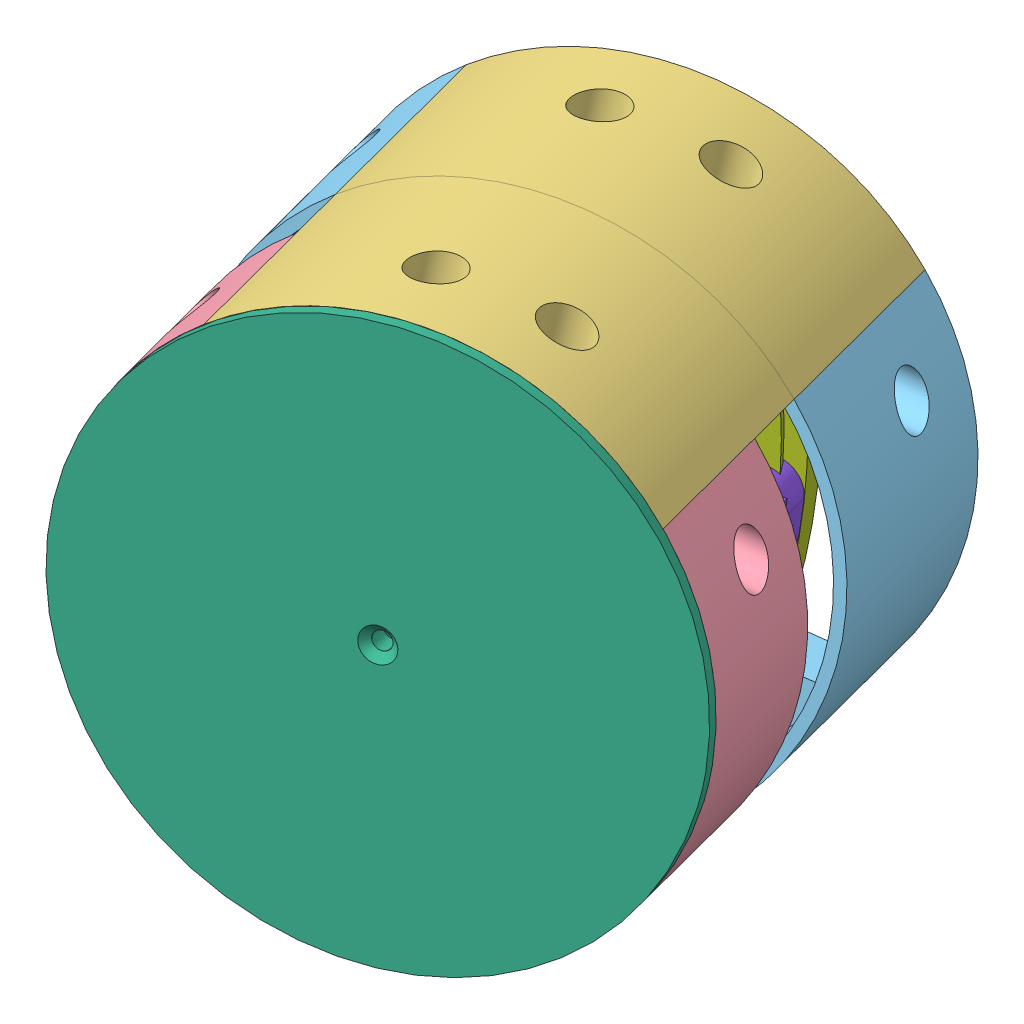
SolidWorks assembly BeaconAssembly, configuration Default. Lengths in mm.
Overall size (130.79 119.05 119.49).
31 component instances, 10 part files, 112 mates.
Components (placement in the parent):
- Makerbeam50-1000mm-5: Makerbeam50-1000mm [40mm] at (-34.6377 -12.5194 95.4893) x (-0.939068 0.162463 0.302916) z (0.122955 0.98171 -0.145351) size (10 10 40)
- MakerBeam-cube-5: MakerBeam-cube [Default] at (-30.5571 -18.2402 94.7014) x (-0.122955 -0.98171 0.145351) z (-0.939068 0.162463 0.302916) size (10 10 10)
- MakerBeam-cube-6: MakerBeam-cube [Default] at (-56.1168 -23.8791 34.9946) x (-0.122955 -0.98171 0.145351) z (-0.32099 -0.099249 -0.941868) size (10 10 10)
- Makerbeam50-1000mm-6: Makerbeam50-1000mm [60mm] at (-36.8574 -17.9242 91.5067) x (-0.939068 0.162463 0.302916) z (-0.32099 -0.099249 -0.941868) size (10 10 60)
- MakerBeam-cube-7: MakerBeam-cube [Default] at (-29.7195 26.749 89.6752) x (-0.939068 0.162463 0.302916) z (0.122955 0.98171 -0.145351) size (10 10 10)
- Makerbeam50-1000mm-7: Makerbeam50-1000mm [60mm] at (-30.7097 31.1613 84.2391) x (-0.939068 0.162463 0.302916) z (-0.32099 -0.099249 -0.941868) size (10 10 60)
- MakerBeam-cube-8: MakerBeam-cube [Default] at (-52.1888 19.8016 23.7445) x (-0.32099 -0.099249 -0.941868) z (0.122955 0.98171 -0.145351) size (10 10 10)
- Makerbeam50-1000mm-8: Makerbeam50-1000mm [40mm] at (-57.107 -19.4668 29.5585) x (-0.939068 0.162463 0.302916) z (0.122955 0.98171 -0.145351) size (10 10 40)
- BeaconShapeFix20mm-1: BeaconShapeFix20mm [Default] at (-65.6435 1.2958 24.9713) x (0.122955 0.98171 -0.145351) z (0.939068 -0.162463 -0.302916) size (20.5 40 70)
- BeaconShapeFix20mm-2: BeaconShapeFix20mm [Default] at (-65.6435 1.2958 24.9713) x (-0.122955 -0.98171 0.145351) z (-0.939068 0.162463 0.302916) size (20.5 40 70)
- Makerbeam50-1000mm-9: Makerbeam50-1000mm [40mm] at (-75.8883 -16.2176 35.6168) x (-0.939068 0.162463 0.302916) z (0.122955 0.98171 -0.145351) size (10 10 40)
- MakerBeam-cube-9: MakerBeam-cube [Default] at (-70.9701 23.0508 29.8028) x (-0.32099 -0.099249 -0.941868) z (0.122955 0.98171 -0.145351) size (10 10 10)
- Makerbeam50-1000mm-10: Makerbeam50-1000mm [60mm] at (-49.491 34.4106 90.2974) x (-0.939068 0.162463 0.302916) z (-0.32099 -0.099249 -0.941868) size (10 10 60)
- MakerBeam-cube-10: MakerBeam-cube [Default] at (-48.5009 29.9983 95.7335) x (-0.939068 0.162463 0.302916) z (0.122955 0.98171 -0.145351) size (10 10 10)
- Makerbeam50-1000mm-11: Makerbeam50-1000mm [60mm] at (-55.6388 -14.6749 97.565) x (-0.939068 0.162463 0.302916) z (-0.32099 -0.099249 -0.941868) size (10 10 60)
- MakerBeam-cube-11: MakerBeam-cube [Default] at (-74.8981 -20.6299 41.0529) x (-0.122955 -0.98171 0.145351) z (-0.32099 -0.099249 -0.941868) size (10 10 10)
- MakerBeam-cube-12: MakerBeam-cube [Default] at (-49.3385 -14.991 100.7598) x (-0.122955 -0.98171 0.145351) z (-0.939068 0.162463 0.302916) size (10 10 10)
- Makerbeam50-1000mm-12: Makerbeam50-1000mm [40mm] at (-53.419 -9.2701 101.5476) x (-0.939068 0.162463 0.302916) z (0.122955 0.98171 -0.145351) size (10 10 40)
- BeaconShapeFix20mm-3: BeaconShapeFix20mm [Default] at (-39.9643 9.2357 100.3207) x (0.122955 0.98171 -0.145351) z (-0.939068 0.162463 0.302916) size (20.5 40 70)
- BeaconShapeFix20mm-4: BeaconShapeFix20mm [Default] at (-39.9643 9.2357 100.3207) x (-0.122955 -0.98171 0.145351) z (0.939068 -0.162463 -0.302916) size (20.5 40 70)
- BeaconShapeFix60mmTop-4: BeaconShapeFix60mmTop [Default] at (-39.9643 9.2357 100.3207) x (-0.939068 0.162463 0.302916) z (-0.122955 -0.98171 0.145351) size (35.5 28 70)
- BeaconShapeFix60mm-3: BeaconShapeFix60mm [Default] at (-65.6435 1.2958 24.9713) x (-0.939068 0.162463 0.302916) z (0.122955 0.98171 -0.145351) size (35.5 40 70)
- BeaconShapeFix60mm-4: BeaconShapeFix60mm [Default] at (-65.6435 1.2958 24.9713) x (0.939068 -0.162463 -0.302916) z (-0.122955 -0.98171 0.145351) size (35.5 40 70)
- BeaconShapeTop-1: BeaconShapeTop [Default] at (-39.2754 9.4261 102.1893) x (0.939068 -0.162463 -0.302916) z (-0.32099 -0.099249 -0.941868) size (99 99 5)
- BeaconShapeFix60mmTop-5: BeaconShapeFix60mmTop [Default] at (-39.9643 9.2357 100.3207) x (0.939068 -0.162463 -0.302916) z (0.122955 0.98171 -0.145351) size (35.5 28 70)
- tofSupportAssembly-3: tofSupportAssembly [Default] at (-60.9909 65.9256 -3.2511) x (0.939068 -0.162463 -0.302916) z (-0.122955 -0.98171 0.145351) size (100 34.8 100)
  - Vl530xSupport-1: Vl530xSupport [Default] at (-71.557 41.8738 68.122) size (100 18 100)
  - TofSupport-1: TofSupport [Default] at (-121.3617 51.8738 62.8047) x (-0.10616 0 0.994349) z (-0.994349 0 -0.10616) size (15.71 30.8 10.03)
  - CJVL53L0XV2-1: CJVL53L0XV2 [Default] at (28.785 64.2738 78.8349) x (0 -1 0) z (0.994349 0 0.10616) size (24.8 12.4 11)
  - TofSupport-2: TofSupport [Default] at (-121.4599 51.8738 72.3847) x (0.085109 0 0.996372) z (-0.996372 0 0.085109) size (15.71 30.8 10.03)
- BeaconShapeCentralBracket_ParallelCorner10x30x7-3: BeaconShapeCentralBracket_ParallelCorner10x30x7 [Default] at (-43.2831 27.0834 80.4601) x (0.939068 -0.162463 -0.302916) z (-0.122955 -0.98171 0.145351) size (30 18 40)
Mates (geometry in assembly coordinates):
- Concentric1: concentric anti-aligned: cylinder of ? through (22.887 40.6344 65.8442) axis (0 0 -1) radius 1.25; cylinder of ? through (22.887 40.6344 75.8442) axis (0 0 1) radius 1.25
- Coincident1: coincident anti-aligned: plane of ? through (22.887 40.6344 65.8442) normal (0 0 1); plane of ? through (22.887 40.6344 65.8442) normal (0 0 -1)
- Coincident2: coincident aligned: plane of ? through (27.887 45.6344 65.8442) normal (1 0 0); plane of ? through (27.887 35.6344 75.8442) normal (1 0 0)
- Concentric2: concentric anti-aligned: cylinder of ? through (22.887 35.6344 70.8442) axis (0 -1 0) radius 1.25; cylinder of ? through (22.887 45.6344 70.8442) axis (0 1 0) radius 1.25
- Coincident3: coincident anti-aligned: plane of ? through (17.887 45.6344 75.8442) normal (0 1 0); plane of ? through (22.887 45.6344 70.8442) normal (0 -1 0)
- Concentric3: concentric anti-aligned: cylinder of ? through (22.887 45.6344 70.8442) axis (0 1 0) radius 1.25; cylinder of ? through (22.887 105.6344 70.8442) axis (0 -1 0) radius 1.25
- Coincident4: coincident anti-aligned: plane of ? through (22.887 105.6344 70.8442) normal (0 1 0); plane of ? through (27.887 105.6344 75.8442) normal (0 -1 0)
- Coincident5: coincident aligned: plane of ? through (27.887 45.6344 75.8442) normal (1 0 0); plane of ? through (27.887 105.6344 75.8442) normal (1 0 0)
- Concentric4: concentric aligned: cylinder of ? through (22.887 40.6344 65.8442) axis (0 0 -1) radius 1.25; cylinder of ? through (22.887 40.6344 15.8442) axis (0 0 -1) radius 1.25
- Coincident6: coincident aligned: plane of ? through (27.887 45.6344 65.8442) normal (1 0 0); plane of ? through (27.887 35.6344 15.8442) normal (1 0 0)
- Coincident7: coincident anti-aligned: plane of ? through (22.887 40.6344 25.8442) normal (0 0 -1); plane of ? through (17.887 35.6344 25.8442) normal (0 0 1)
- Concentric5: concentric anti-aligned: cylinder of ? through (22.887 45.6344 20.8442) axis (0 1 0) radius 1.25; cylinder of ? through (22.887 35.6344 20.8442) axis (0 -1 0) radius 1.25
- Coincident8: coincident anti-aligned: plane of ? through (22.887 45.6344 20.8442) normal (0 -1 0); plane of ? through (22.887 45.6344 20.8442) normal (0 1 0)
- Coincident9: coincident aligned: plane of ? through (27.887 45.6344 19.3442) normal (1 0 0); plane of ? through (27.887 35.6344 15.8442) normal (1 0 0)
- Concentric6: concentric anti-aligned: cylinder of ? through (22.887 45.6344 20.8442) axis (0 1 0) radius 1.25; cylinder of ? through (22.887 105.6344 20.8442) axis (0 -1 0) radius 1.25
- Coincident10: coincident anti-aligned: plane of ? through (22.887 105.6344 20.8442) normal (0 1 0); plane of ? through (27.887 105.6344 15.8442) normal (0 -1 0)
- Coincident11: coincident aligned: plane of ? through (17.887 45.6344 25.8442) normal (0 0 1); plane of ? through (27.887 105.6344 25.8442) normal (0 0 1)
- Concentric7: concentric anti-aligned: cylinder of ? through (22.887 110.6344 75.8442) axis (0 0 1) radius 1.25; cylinder of ? through (22.887 110.6344 65.8442) axis (0 0 -1) radius 1.25
- Coincident12: coincident aligned: plane of ? through (27.887 115.6344 75.8442) normal (0 1 0); plane of ? through (24.387 115.6344 65.8442) normal (0 1 0)
- Coincident13: coincident anti-aligned: plane of ? through (22.887 110.6344 65.8442) normal (0 0 -1); plane of ? through (22.887 110.6344 65.8442) normal (0 0 1)
- Concentric8: concentric anti-aligned: cylinder of MakerBeam-cube-5 through (-36.8574 -17.9242 91.5067) axis (-0.32099 -0.099249 -0.941868) radius 1.25; cylinder of Makerbeam50-1000mm-6 through (-56.1168 -23.8791 34.9946) axis (0.32099 0.099249 0.941868) radius 1.25
- Concentric9: concentric anti-aligned: cylinder of MakerBeam-cube-7 through (-30.7097 31.1613 84.2391) axis (-0.32099 -0.099249 -0.941868) radius 1.25; cylinder of Makerbeam50-1000mm-7 through (-49.9691 25.2064 27.7271) axis (0.32099 0.099249 0.941868) radius 1.25
- Coincident14: coincident anti-aligned: plane of MakerBeam-cube-7 through (-34.7902 36.8822 85.027) normal (-0.32099 -0.099249 -0.941868); plane of Makerbeam50-1000mm-7 through (-30.7097 31.1613 84.2391) normal (0.32099 0.099249 0.941868)
- Concentric10: concentric anti-aligned: cylinder of Makerbeam50-1000mm-5 through (-29.7195 26.749 89.6752) axis (-0.122955 -0.98171 0.145351) radius 1.25; cylinder of MakerBeam-cube-7 through (-28.49 36.5661 88.2217) axis (0.122955 0.98171 -0.145351) radius 1.25
- Concentric11: concentric aligned: cylinder of MakerBeam-cube-6 through (-58.3365 -29.2839 31.012) axis (-0.122955 -0.98171 0.145351) radius 1.25; cylinder of Makerbeam50-1000mm-8 through (-52.1888 19.8016 23.7445) axis (-0.122955 -0.98171 0.145351) radius 1.25
- Coincident15: coincident aligned: plane of MakerBeam-cube-5 through (-40.938 -12.2033 92.2945) normal (0.122955 0.98171 -0.145351); plane of Makerbeam50-1000mm-6 through (-50.8067 -19.7829 32.7533) normal (0.122955 0.98171 -0.145351)
- Coincident16: coincident anti-aligned: plane of Makerbeam50-1000mm-5 through (-29.7195 26.749 89.6752) normal (0.122955 0.98171 -0.145351); plane of MakerBeam-cube-7 through (-29.7195 26.749 89.6752) normal (-0.122955 -0.98171 0.145351)
- Coincident17: coincident anti-aligned: plane of MakerBeam-cube-5 through (-42.1675 -22.0204 93.748) normal (-0.32099 -0.099249 -0.941868); plane of Makerbeam50-1000mm-6 through (-36.8574 -17.9242 91.5067) normal (0.32099 0.099249 0.941868)
- Coincident18: coincident anti-aligned: plane of Makerbeam50-1000mm-7 through (-49.9691 25.2064 27.7271) normal (-0.32099 -0.099249 -0.941868); plane of MakerBeam-cube-8 through (-44.659 29.3026 25.4857) normal (0.32099 0.099249 0.941868)
- Concentric12: concentric anti-aligned: cylinder of Makerbeam50-1000mm-7 through (-49.9691 25.2064 27.7271) axis (0.32099 0.099249 0.941868) radius 1.25; cylinder of MakerBeam-cube-8 through (-53.179 24.2139 18.3084) axis (-0.32099 -0.099249 -0.941868) radius 1.25
- Coincident19: coincident aligned: plane of MakerBeam-cube-6 through (-64.6368 -28.9679 27.8173) normal (-0.939068 0.162463 0.302916); plane of Makerbeam50-1000mm-8 through (-55.2792 21.1101 29.9684) normal (-0.939068 0.162463 0.302916)
- Concentric13: concentric anti-aligned: cylinder of MakerBeam-cube-6 through (-59.3267 -24.8716 25.5759) axis (-0.32099 -0.099249 -0.941868) radius 1.25; cylinder of Makerbeam50-1000mm-6 through (-56.1168 -23.8791 34.9946) axis (0.32099 0.099249 0.941868) radius 1.25
- Coincident20: coincident aligned: plane of MakerBeam-cube-7 through (-34.7902 36.8822 85.027) normal (-0.939068 0.162463 0.302916); plane of Makerbeam50-1000mm-7 through (-54.0496 30.9272 28.5149) normal (-0.939068 0.162463 0.302916)
- Coincident21: coincident aligned: plane of Makerbeam50-1000mm-5 through (-29.5232 27.489 94.8389) normal (0.32099 0.099249 0.941868); plane of MakerBeam-cube-7 through (-31.5804 37.8747 94.4456) normal (0.32099 0.099249 0.941868)
- Coincident22: coincident anti-aligned: plane of MakerBeam-cube-6 through (-54.0166 -20.7754 23.3346) normal (0.122955 0.98171 -0.145351); plane of Makerbeam50-1000mm-8 through (-57.107 -19.4668 29.5585) normal (-0.122955 -0.98171 0.145351)
- Coincident23: coincident anti-aligned: plane of MakerBeam-cube-6 through (-56.1168 -23.8791 34.9946) normal (0.32099 0.099249 0.941868); plane of Makerbeam50-1000mm-6 through (-56.1168 -23.8791 34.9946) normal (-0.32099 -0.099249 -0.941868)
- Coincident24: coincident aligned: plane of MakerBeam-cube-6 through (-64.6368 -28.9679 27.8173) normal (-0.939068 0.162463 0.302916); plane of Makerbeam50-1000mm-6 through (-60.9966 -24.5394 36.7272) normal (-0.939068 0.162463 0.302916)
- Concentric14: concentric anti-aligned: cylinder of MakerBeam-cube-8 through (-50.9592 29.6187 22.291) axis (0.122955 0.98171 -0.145351) radius 1.25; cylinder of Makerbeam50-1000mm-8 through (-52.1888 19.8016 23.7445) axis (-0.122955 -0.98171 0.145351) radius 1.25
- Coincident25: coincident anti-aligned: plane of MakerBeam-cube-8 through (-52.1888 19.8016 23.7445) normal (-0.122955 -0.98171 0.145351); plane of Makerbeam50-1000mm-8 through (-52.1888 19.8016 23.7445) normal (0.122955 0.98171 -0.145351)
- Coincident26: coincident aligned: plane of MakerBeam-cube-8 through (-57.2595 29.9348 19.0962) normal (-0.939068 0.162463 0.302916); plane of Makerbeam50-1000mm-8 through (-55.2792 21.1101 29.9684) normal (-0.939068 0.162463 0.302916)
- Coincident27: coincident aligned: plane of ? through (27.887 115.6344 75.8442) normal (0 1 0); plane of MakerBeam-cube-5
- Concentric15: concentric aligned: cylinder of Makerbeam50-1000mm-5 through (-29.7195 26.749 89.6752) axis (-0.122955 -0.98171 0.145351) radius 1.25; cylinder of MakerBeam-cube-5 through (-35.8672 -22.3365 96.9428) axis (-0.122955 -0.98171 0.145351) radius 1.25
- Concentric16: concentric aligned: cylinder of ? through (22.887 110.6344 15.8442) axis (0 0 -1) radius 1.25; cylinder of ? through (22.887 110.6344 65.8442) axis (0 0 -1) radius 1.25
- Coincident29: coincident anti-aligned: plane of Makerbeam50-1000mm-6; plane of ? through (78.412 25.8981 91.5235) normal (-1 0 0)
- Coincident30: coincident aligned: plane of Makerbeam50-1000mm-6; plane of ? through (100.2393 25.8981 91.5235) normal (0 0 1)
- Coincident31: coincident aligned: plane of Makerbeam50-1000mm-8; plane of ? through (96.9996 5.8981 27.9359) normal (0 -1 0)
- Coincident32: coincident aligned: plane of Makerbeam50-1000mm-6; plane of ? through (114.1385 62.6146 110.569) normal (0 0 1)
- Coincident35: coincident anti-aligned: plane of Makerbeam50-1000mm-7 through (-44.659 29.3026 25.4857) normal (0.122955 0.98171 -0.145351); plane of BeaconShapeFix20mm-1 through (-41.4491 30.2951 34.9044) normal (-0.122955 -0.98171 0.145351)
- Coincident36: coincident aligned: plane of MakerBeam-cube-8 through (-47.8689 28.3101 16.067) normal (-0.32099 -0.099249 -0.941868); plane of BeaconShapeFix20mm-1 through (-93.0548 39.7258 30.2635) normal (-0.32099 -0.099249 -0.941868)
- Coincident37: coincident aligned: plane of Makerbeam50-1000mm-7 through (-45.0893 25.8666 25.9945) normal (0.939068 -0.162463 -0.302916); plane of BeaconShapeFix20mm-1 through (-39.5962 45.0889 32.7141) normal (0.939068 -0.162463 -0.302916)
- Coincident38: coincident anti-aligned: plane of Makerbeam50-1000mm-6 through (-55.323 -29.0314 35.267) normal (-0.122955 -0.98171 0.145351); plane of BeaconShapeFix20mm-2 through (-76.9984 -23.7336 52.7129) normal (0.122955 0.98171 -0.145351)
- Coincident39: coincident aligned: plane of ? through (96.9996 5.8981 27.9359) normal (0 -1 0); plane of BeaconShapeFix20mm-2
- Coincident40: coincident aligned: plane of Makerbeam50-1000mm-6 through (-52.0362 -29.6 34.2068) normal (0.939068 -0.162463 -0.302916); plane of BeaconShapeFix20mm-2 through (-48.8263 -28.6075 43.6255) normal (0.939068 -0.162463 -0.302916)
- Coincident41: coincident aligned: plane of BeaconShapeFix20mm-1; plane of ? through (29.8244 5.8981 95.111) normal (0 -1 0)
- Coincident42: coincident aligned: plane of Makerbeam50-1000mm-10 through (-72.831 34.1765 34.5732) normal (-0.939068 0.162463 0.302916); plane of MakerBeam-cube-10 through (-53.5716 40.1315 91.0853) normal (-0.939068 0.162463 0.302916)
- Coincident43: coincident anti-aligned: plane of Makerbeam50-1000mm-9 through (-70.9701 23.0508 29.8028) normal (0.122955 0.98171 -0.145351); plane of MakerBeam-cube-9 through (-70.9701 23.0508 29.8028) normal (-0.122955 -0.98171 0.145351)
- Coincident44: coincident aligned: plane of Makerbeam50-1000mm-9 through (-74.0605 24.3594 36.0267) normal (-0.939068 0.162463 0.302916); plane of MakerBeam-cube-9 through (-76.0409 33.184 25.1545) normal (-0.939068 0.162463 0.302916)
- Coincident45: coincident anti-aligned: plane of Makerbeam50-1000mm-9 through (-75.8883 -16.2176 35.6168) normal (-0.122955 -0.98171 0.145351); plane of MakerBeam-cube-11 through (-72.7979 -17.5261 29.3929) normal (0.122955 0.98171 -0.145351)
- Coincident46: coincident aligned: plane of Makerbeam50-1000mm-11 through (-79.7779 -21.2901 42.7855) normal (-0.939068 0.162463 0.302916); plane of MakerBeam-cube-11 through (-83.4182 -25.7186 33.8756) normal (-0.939068 0.162463 0.302916)
- Coincident47: coincident aligned: plane of MakerBeam-cube-10 through (-50.3617 41.124 100.5039) normal (0.32099 0.099249 0.941868); plane of Makerbeam50-1000mm-12 through (-48.3045 30.7382 100.8973) normal (0.32099 0.099249 0.941868)
- Coincident48: coincident anti-aligned: plane of Makerbeam50-1000mm-11 through (-74.8981 -20.6299 41.0529) normal (-0.32099 -0.099249 -0.941868); plane of MakerBeam-cube-11 through (-74.8981 -20.6299 41.0529) normal (0.32099 0.099249 0.941868)
- Concentric17: concentric anti-aligned: cylinder of Makerbeam50-1000mm-9 through (-70.9701 23.0508 29.8028) axis (-0.122955 -0.98171 0.145351) radius 1.25; cylinder of MakerBeam-cube-9 through (-69.7406 32.8679 28.3493) axis (0.122955 0.98171 -0.145351) radius 1.25
- Concentric18: concentric anti-aligned: cylinder of MakerBeam-cube-10 through (-47.2713 39.8154 94.28) axis (0.122955 0.98171 -0.145351) radius 1.25; cylinder of Makerbeam50-1000mm-12 through (-48.5009 29.9983 95.7335) axis (-0.122955 -0.98171 0.145351) radius 1.25
- Concentric19: concentric anti-aligned: cylinder of Makerbeam50-1000mm-11 through (-74.8981 -20.6299 41.0529) axis (0.32099 0.099249 0.941868) radius 1.25; cylinder of MakerBeam-cube-12 through (-55.6388 -14.6749 97.565) axis (-0.32099 -0.099249 -0.941868) radius 1.25
- Concentric20: concentric aligned: cylinder of Makerbeam50-1000mm-9 through (-70.9701 23.0508 29.8028) axis (-0.122955 -0.98171 0.145351) radius 1.25; cylinder of MakerBeam-cube-11 through (-77.1179 -26.0347 37.0703) axis (-0.122955 -0.98171 0.145351) radius 1.25
- Coincident49: coincident anti-aligned: plane of MakerBeam-cube-10 through (-48.5009 29.9983 95.7335) normal (-0.122955 -0.98171 0.145351); plane of Makerbeam50-1000mm-12 through (-48.5009 29.9983 95.7335) normal (0.122955 0.98171 -0.145351)
- Coincident50: coincident anti-aligned: plane of Makerbeam50-1000mm-11 through (-55.6388 -14.6749 97.565) normal (0.32099 0.099249 0.941868); plane of MakerBeam-cube-12 through (-60.9489 -18.7711 99.8063) normal (-0.32099 -0.099249 -0.941868)
- Coincident51: coincident anti-aligned: plane of MakerBeam-cube-9 through (-63.4403 32.5519 31.544) normal (0.32099 0.099249 0.941868); plane of Makerbeam50-1000mm-10 through (-68.7504 28.4556 33.7854) normal (-0.32099 -0.099249 -0.941868)
- Concentric21: concentric anti-aligned: cylinder of MakerBeam-cube-9 through (-71.9603 27.4631 24.3667) axis (-0.32099 -0.099249 -0.941868) radius 1.25; cylinder of Makerbeam50-1000mm-10 through (-68.7504 28.4556 33.7854) axis (0.32099 0.099249 0.941868) radius 1.25
- Coincident52: coincident aligned: plane of Makerbeam50-1000mm-9 through (-74.0605 24.3594 36.0267) normal (-0.939068 0.162463 0.302916); plane of MakerBeam-cube-11 through (-83.4182 -25.7186 33.8756) normal (-0.939068 0.162463 0.302916)
- Concentric22: concentric anti-aligned: cylinder of Makerbeam50-1000mm-11 through (-74.8981 -20.6299 41.0529) axis (0.32099 0.099249 0.941868) radius 1.25; cylinder of MakerBeam-cube-11 through (-78.108 -21.6224 31.6342) axis (-0.32099 -0.099249 -0.941868) radius 1.25
- Coincident53: coincident anti-aligned: plane of Makerbeam50-1000mm-10 through (-49.491 34.4106 90.2974) normal (0.32099 0.099249 0.941868); plane of MakerBeam-cube-10 through (-53.5716 40.1315 91.0853) normal (-0.32099 -0.099249 -0.941868)
- Coincident54: coincident aligned: plane of Makerbeam50-1000mm-11 through (-69.588 -16.5336 38.8116) normal (0.122955 0.98171 -0.145351); plane of MakerBeam-cube-12 through (-59.7193 -8.954 98.3528) normal (0.122955 0.98171 -0.145351)
- Concentric23: concentric anti-aligned: cylinder of Makerbeam50-1000mm-10 through (-68.7504 28.4556 33.7854) axis (0.32099 0.099249 0.941868) radius 1.25; cylinder of MakerBeam-cube-10 through (-49.491 34.4106 90.2974) axis (-0.32099 -0.099249 -0.941868) radius 1.25
- Concentric24: concentric aligned: cylinder of MakerBeam-cube-12 through (-54.6486 -19.0872 103.0011) axis (-0.122955 -0.98171 0.145351) radius 1.25; cylinder of Makerbeam50-1000mm-12 through (-48.5009 29.9983 95.7335) axis (-0.122955 -0.98171 0.145351) radius 1.25
- Coincident55: coincident aligned: plane of MakerBeam-cube-5 through (-42.1675 -22.0204 93.748) normal (-0.122955 -0.98171 0.145351); plane of MakerBeam-cube-12 through (-60.9489 -18.7711 99.8063) normal (-0.122955 -0.98171 0.145351)
- Coincident56: coincident aligned: plane of Makerbeam50-1000mm-5 through (-29.5232 27.489 94.8389) normal (0.32099 0.099249 0.941868); plane of Makerbeam50-1000mm-12 through (-42.2006 29.6822 98.9283) normal (0.32099 0.099249 0.941868)
- Distance1: distance = 10 mm: line of MakerBeam-cube-12 through (-51.5582 -20.3958 96.7772) axis (0.32099 0.099249 0.941868); line of MakerBeam-cube-5 through (-42.1675 -22.0204 93.748) axis (0.32099 0.099249 0.941868)
- Coincident58: coincident anti-aligned: plane of ? through (48.412 15.8981 31.5235) normal (1 0 0); plane of Makerbeam50-1000mm-10
- Coincident59: coincident aligned: plane of ? through (26.5847 15.8981 31.5235) normal (0 0 -1); plane of Makerbeam50-1000mm-10
- Coincident60: coincident anti-aligned: plane of Makerbeam50-1000mm-7 through (-50.7629 30.3586 27.4547) normal (0.122955 0.98171 -0.145351); plane of BeaconShapeFix20mm-3 through (-56.7815 39.139 81.6666) normal (-0.122955 -0.98171 0.145351)
- Coincident61: coincident aligned: plane of MakerBeam-cube-7 through (-31.5804 37.8747 94.4456) normal (0.32099 0.099249 0.941868); plane of BeaconShapeFix20mm-3 through (-4.2936 36.7522 85.2646) normal (0.32099 0.099249 0.941868)
- Coincident62: coincident aligned: plane of Makerbeam50-1000mm-10 through (-72.831 34.1765 34.5732) normal (-0.939068 0.162463 0.302916); plane of BeaconShapeFix20mm-3 through (-54.9286 53.9328 79.4762) normal (-0.939068 0.162463 0.302916)
- Coincident66: coincident aligned: plane of Makerbeam50-1000mm-12; plane of ? through (-9.6384 49.1142 96.8254) normal (0.408012 0.184445 0.894151)
- Coincident68: coincident anti-aligned: plane of Makerbeam50-1000mm-5; plane of ? through (-1.967 47.18 89.7536) normal (0.911986 -0.127943 -0.389759)
- Coincident69: coincident anti-aligned: line of Makerbeam50-1000mm-12 through (-12.8304 49.562 98.1896) axis (0.911986 -0.127943 -0.389759); line of ? through (-0.5185 47.8347 92.9278) axis (-0.911986 0.127943 0.389759)
- Coincident70: coincident anti-aligned: line of MakerBeam-cube-10 through (-17.0578 89.3728 91.9065) axis (0.911986 -0.127943 -0.389759); line of ? through (1.1819 86.8139 84.1113) axis (-0.911986 0.127943 0.389759)
- Coincident71: coincident anti-aligned: plane of Makerbeam50-1000mm-5; plane of ?
- Coincident83: coincident aligned: line of BeaconShapeFix20mm-2 through (-102.8162 -27.3794 40.6614) axis (0.32099 0.099249 0.941868); line of BeaconShapeFix60mm-3 through (-102.8162 -27.3794 40.6614) axis (0.32099 0.099249 0.941868)
- Coincident85: coincident aligned: plane of BeaconShapeFix20mm-1 through (-93.0548 39.7258 30.2635) normal (-0.32099 -0.099249 -0.941868); plane of BeaconShapeFix60mm-3 through (-101.3142 -26.2208 40.0275) normal (-0.32099 -0.099249 -0.941868)
- Coincident87: coincident aligned: plane of BeaconShapeFix20mm-2 through (-38.2322 -37.1343 19.6791) normal (-0.32099 -0.099249 -0.941868); plane of BeaconShapeFix60mm-3 through (-101.3142 -26.2208 40.0275) normal (-0.32099 -0.099249 -0.941868)
- Parallel4: parallel anti-aligned: plane of Makerbeam50-1000mm-10 through (-73.6302 27.7954 35.518) normal (-0.939068 0.162463 0.302916); plane of BeaconShapeFix60mm-3 through (-69.6211 35.169 43.9919) normal (0.939068 -0.162463 -0.302916)
- Coincident90: coincident anti-aligned: plane of Makerbeam50-1000mm-6 through (-51.237 -23.2189 33.262) normal (0.939068 -0.162463 -0.302916); plane of BeaconShapeFix60mm-4 through (-48.8263 -28.6075 43.6255) normal (-0.939068 0.162463 0.302916)
- Coincident91: coincident aligned: plane of MakerBeam-cube-8 through (-50.9592 29.6187 22.291) normal (0.122955 0.98171 -0.145351); plane of BeaconShapeFix60mm-4 through (-41.4491 30.2951 34.9044) normal (0.122955 0.98171 -0.145351)
- Coincident92: coincident: line of MakerBeam-cube-6 through (-50.8067 -19.7829 32.7533) axis (-0.122955 -0.98171 0.145351); plane of BeaconShapeFix60mm-4 through (-62.4336 2.2883 34.39) normal (-0.32099 -0.099249 -0.941868)
- Coincident93: coincident anti-aligned: plane of Makerbeam50-1000mm-12 through (-48.3045 30.7382 100.8973) normal (0.32099 0.099249 0.941868); plane of BeaconShapeTop-1 through (-39.9174 9.2276 100.3056) normal (-0.32099 -0.099249 -0.941868)
- Coincident94: coincident anti-aligned: plane of Makerbeam50-1000mm-12 through (-45.4873 30.2509 99.9885) normal (-0.939068 0.162463 0.302916); plane of BeaconShapeTop-1 through (-50.7265 -9.1168 104.8607) normal (0.939068 -0.162463 -0.302916)
- Coincident95: coincident anti-aligned: line of Makerbeam50-1000mm-12 through (-56.5094 -7.9615 107.7715) axis (0.939068 -0.162463 -0.302916); line of BeaconShapeTop-1 through (-50.4055 -9.0176 105.8025) axis (-0.939068 0.162463 0.302916)
- Coincident96: coincident aligned: plane of ? through (119.0125 85.0481 84.6788) normal (0 1 0); plane of ? through (122.8437 85.0481 45.5673) normal (0 1 0)
- Coincident106: coincident anti-aligned: plane of Makerbeam50-1000mm-6 through (-51.237 -23.2189 33.262) normal (0.939068 -0.162463 -0.302916); plane of tofSupportAssembly-3/Vl530xSupport-1 through (-42.0214 -26.5034 63.5931) normal (-0.939068 0.162463 0.302916)
- Coincident107: coincident aligned: plane of Makerbeam50-1000mm-6 through (-58.1402 -28.544 36.1757) normal (-0.122955 -0.98171 0.145351); plane of tofSupportAssembly-3/Vl530xSupport-1 through (-36.3869 -27.4782 61.7756) normal (-0.122955 -0.98171 0.145351)
- Coincident109: coincident anti-aligned: plane of Makerbeam50-1000mm-6 through (-52.0362 -29.6 34.2068) normal (0.939068 -0.162463 -0.302916); plane of BeaconShapeFix60mmTop-5 through (-29.2515 34.0666 70.6954) normal (-0.939068 0.162463 0.302916)
- Coincident111: coincident: line of Makerbeam50-1000mm-6 through (-52.0362 -29.6 34.2068) axis (0.32099 0.099249 0.941868); plane of BeaconShapeFix60mmTop-5 through (-36.6287 -24.836 79.4164) normal (-0.122955 -0.98171 0.145351)
- Coincident113: coincident anti-aligned: plane of BeaconShapeFix60mmTop-5 through (-47.0261 7.0522 79.5996) normal (-0.32099 -0.099249 -0.941868); plane of tofSupportAssembly-3/TofSupport-1 through (-23.2339 -1.186 72.3594) normal (0.32099 0.099249 0.941868)
- Coincident114: coincident aligned: plane of BeaconShapeFix60mmTop-4 through (-67.3756 47.6657 105.613) normal (0.32099 0.099249 0.941868); plane of BeaconShapeFix60mmTop-5 through (-12.5531 -29.1943 95.0285) normal (0.32099 0.099249 0.941868)
- Coincident115: coincident aligned: plane of BeaconShapeFix60mmTop-4 through (-85.2981 -16.416 95.1157) normal (-0.122955 -0.98171 0.145351); plane of BeaconShapeFix60mmTop-5 through (-36.6287 -24.836 79.4164) normal (-0.122955 -0.98171 0.145351)
- Coincident118: coincident aligned: plane of Makerbeam50-1000mm-12 through (-42.2006 29.6822 98.9283) normal (0.32099 0.099249 0.941868); plane of BeaconShapeCentralBracket_ParallelCorner10x30x7-3 through (-47.1188 -9.5862 104.7423) normal (0.32099 0.099249 0.941868)
- Coincident120: coincident anti-aligned: plane of Makerbeam50-1000mm-5 through (-32.8099 28.0576 95.8991) normal (-0.939068 0.162463 0.302916); plane of BeaconShapeCentralBracket_ParallelCorner10x30x7-3 through (-38.8676 -11.5631 98.3695) normal (0.939068 -0.162463 -0.302916)
- Coincident121: coincident anti-aligned: line of MakerBeam-cube-10 through (-51.5912 31.3069 101.9575) axis (0.939068 -0.162463 -0.302916); line of BeaconShapeCentralBracket_ParallelCorner10x30x7-3 through (-32.8099 28.0576 95.8991) axis (-0.939068 0.162463 0.302916)
- Coincident122: coincident anti-aligned: plane of Makerbeam50-1000mm-11 through (-74.1043 -25.7821 41.3253) normal (-0.122955 -0.98171 0.145351); plane of BeaconShapeFix20mm-4 through (-35.9867 -24.6375 81.3002) normal (0.122955 0.98171 -0.145351)
- Coincident123: coincident anti-aligned: plane of BeaconShapeFix20mm-2 through (-24.2385 -34.7824 57.131) normal (0.32099 0.099249 0.941868); plane of BeaconShapeFix20mm-4 through (-89.9766 -23.4094 78.3362) normal (-0.32099 -0.099249 -0.941868)
- Coincident124: coincident aligned: line of BeaconShapeFix20mm-4 through (-11.3989 -30.8124 94.8057) axis (-0.32099 -0.099249 -0.941868); line of BeaconShapeFix60mmTop-5 through (-11.3989 -30.8124 94.8057) axis (-0.32099 -0.099249 -0.941868)
